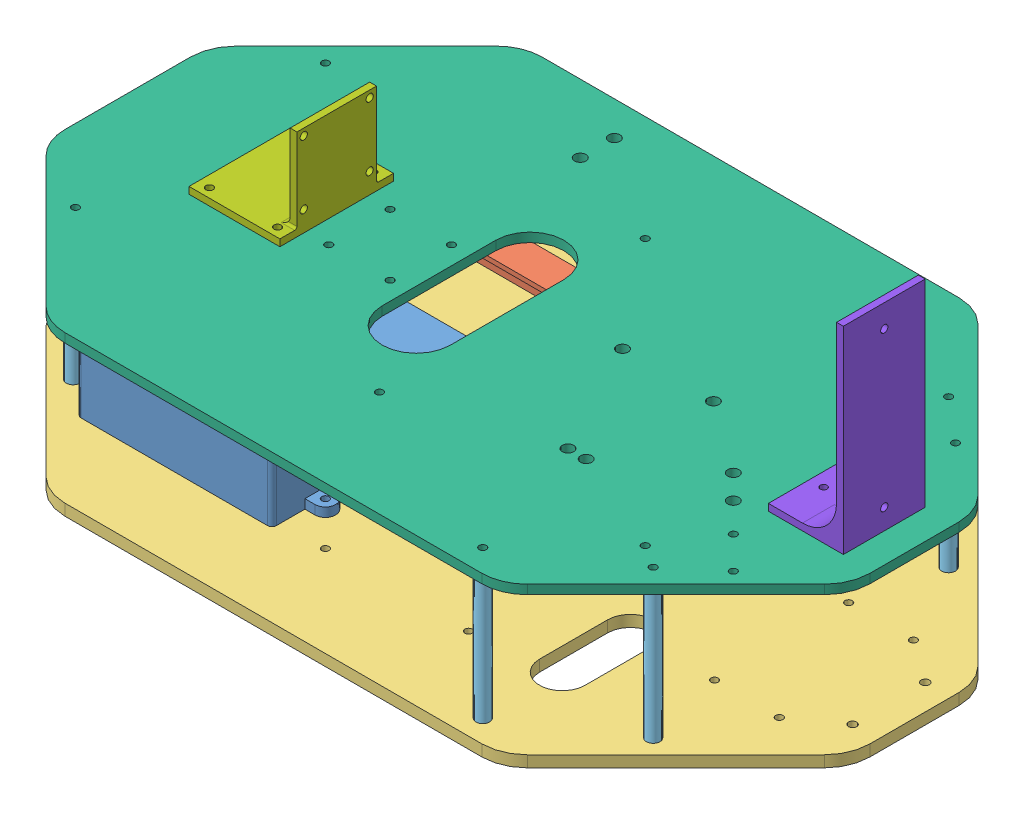
SolidWorks assembly Assemble, configuration Default. Lengths in mm.
Overall size (410.12 157 410.12).
13 component instances, 8 part files, 31 mates.
Components (placement in the parent):
- powerPack-1: powerPack [Default] at (-34.0621 21.3954 119.5667) x (-1 0 0) z (0 0 1) size (104 27 139)
- door-2: door [Default] at (-135.2447 21.3954 95.2049) x (1 0 0) z (0 0 -1) size (94 8 15)
- lowerBase-1: lowerBase [Default] at (-81.8861 -6.6046 151.4136) x (0.707107 0 0.707107) z (-0.707107 0 0.707107) size (290 5 290)
- switch-1: switch [Default] at (89.5127 -1.6046 82.4695) size (40 8 20)
- standing-1: standing [Default] at (-88.606 -1.6046 216.9423) size (6 61 6)
- standing-2: standing [Default] at (130.6581 -1.6046 255.9241) size (6 61 6)
- standing-3: standing [Default] at (175.6581 -1.6046 225.9241) size (6 61 6)
- standing-4: standing [Default] at (130.6581 -1.6046 65.9241) size (6 61 6)
- standing-5: standing [Default] at (175.6581 -1.6046 95.9241) size (6 61 6)
- standing-6: standing [Default] at (-88.606 -1.6046 106.9423) size (6 61 6)
- upperBase-1: upperBase [Default] at (48.5261 59.3954 160.9241) x (0.707107 0 0.707107) z (-0.707107 0 0.707107) size (290 4 290)
- LIDAR-1: LIDAR [Default] at (-31.606 89.8882 163.5193) x (0 0 -1) z (0 -1 0) size (50 40 40)
- wifi-1: wifi [Default] at (212.6581 96.6198 156.5995) x (0 1 0) z (0 0 1) size (87 33 36)
Mates (geometry in assembly coordinates):
- Coincident3: coincident anti-aligned: plane of powerPack-1 through (11.894 -1.6046 90.9241) normal (1 0 0); plane of door-2 through (11.894 15.3954 96.9241) normal (-1 0 0)
- Coincident4: coincident anti-aligned: plane of powerPack-1 through (-74.106 15.3954 96.9241) normal (0 0 1); plane of door-2 through (11.894 15.3954 96.9241) normal (0 0 -1)
- Concentric1: concentric anti-aligned: circle of powerPack-1; circle of lowerBase-1
- Concentric2: concentric anti-aligned: circle of powerPack-1; circle of lowerBase-1
- Parallel4: parallel anti-aligned: plane of powerPack-1 through (-34.0621 21.3954 119.5667) normal (0 1 0); plane of door-2 through (-135.2447 21.3954 95.2049) normal (0 -1 0)
- Concentric3: concentric anti-aligned: circle of lowerBase-1; circle of switch-1
- Concentric4: concentric anti-aligned: circle of lowerBase-1; circle of switch-1
- Coincident14: coincident anti-aligned: plane of lowerBase-1 through (-43.2506 -1.6046 75.9241) normal (0 1 0); plane of switch-1 through (89.5127 -1.6046 82.4695) normal (0 -1 0)
- Concentric5: concentric aligned: circle of lowerBase-1; circle of standing-1
- Coincident15: coincident anti-aligned: plane of lowerBase-1 through (-43.2506 -1.6046 75.9241) normal (0 1 0); plane of standing-1 through (-88.606 -1.6046 216.9423) normal (0 -1 0)
- Coincident16: coincident aligned: plane of lowerBase-1 through (-43.2506 -1.6046 75.9241) normal (0 1 0); circle of standing-2
- Concentric6: concentric aligned: circle of lowerBase-1; circle of standing-2
- Coincident17: coincident anti-aligned: plane of lowerBase-1 through (-43.2506 -1.6046 75.9241) normal (0 1 0); plane of standing-3 through (175.6581 -1.6046 225.9241) normal (0 -1 0)
- Concentric7: concentric aligned: circle of lowerBase-1; circle of standing-3
- Coincident19: coincident anti-aligned: plane of lowerBase-1 through (-43.2506 -1.6046 75.9241) normal (0 1 0); plane of standing-5 through (175.6581 -1.6046 95.9241) normal (0 -1 0)
- Coincident20: coincident anti-aligned: plane of lowerBase-1 through (-43.2506 -1.6046 75.9241) normal (0 1 0); plane of standing-6 through (-88.606 -1.6046 106.9423) normal (0 -1 0)
- Coincident21: coincident aligned: plane of lowerBase-1 through (-43.2506 -1.6046 75.9241) normal (0 1 0); circle of standing-4
- Concentric9: concentric aligned: circle of lowerBase-1; circle of standing-5
- Concentric10: concentric aligned: circle of lowerBase-1; circle of standing-4
- Concentric11: concentric aligned: circle of lowerBase-1; circle of standing-6
- Coincident22: coincident anti-aligned: circle of standing-5; plane of upperBase-1 through (-43.2506 59.3954 75.9241) normal (0 -1 0)
- Concentric12: concentric aligned: circle of standing-5; circle of upperBase-1
- Concentric13: concentric aligned: circle of standing-4; circle of upperBase-1
- Coincident24: coincident anti-aligned: plane of powerPack-1 through (-34.0621 -1.6046 119.5667) normal (0 -1 0); plane of lowerBase-1 through (-43.2506 -1.6046 75.9241) normal (0 1 0)
- Parallel5: parallel anti-aligned: plane of powerPack-1 through (-34.0621 21.3954 119.5667) normal (0 1 0); plane of door-2 through (-135.2447 21.3954 95.2049) normal (0 -1 0)
- Coincident26: coincident anti-aligned: plane of powerPack-1 through (-34.0621 21.3954 119.5667) normal (0 1 0); plane of door-2 through (-135.2447 21.3954 95.2049) normal (0 -1 0)
- Coincident27: coincident anti-aligned: plane of upperBase-1 through (-43.2506 63.3954 75.9241) normal (0 1 0); plane of LIDAR-1 through (-31.606 63.3954 163.5193) normal (0 -1 0)
- Coincident30: coincident aligned: circle of upperBase-1; cylinder of LIDAR-1 through (-33.606 63.3954 181.9241) axis (0 1 0) radius 1.6
- Concentric15: concentric anti-aligned: cylinder of upperBase-1 through (-63.606 63.3954 181.9241) axis (0 -1 0) radius 1.6; cylinder of LIDAR-1 through (-63.606 63.3954 181.9241) axis (0 1 0) radius 1.6
- Coincident31: coincident anti-aligned: plane of upperBase-1 through (-43.2506 63.3954 75.9241) normal (0 1 0); plane of wifi-1 through (209.6581 63.3954 143.2413) normal (0 -1 0)
- Coincident32: coincident aligned: circle of upperBase-1; cylinder of wifi-1 through (205.6581 36.3954 160.9241) axis (0 1 0) radius 1.5
